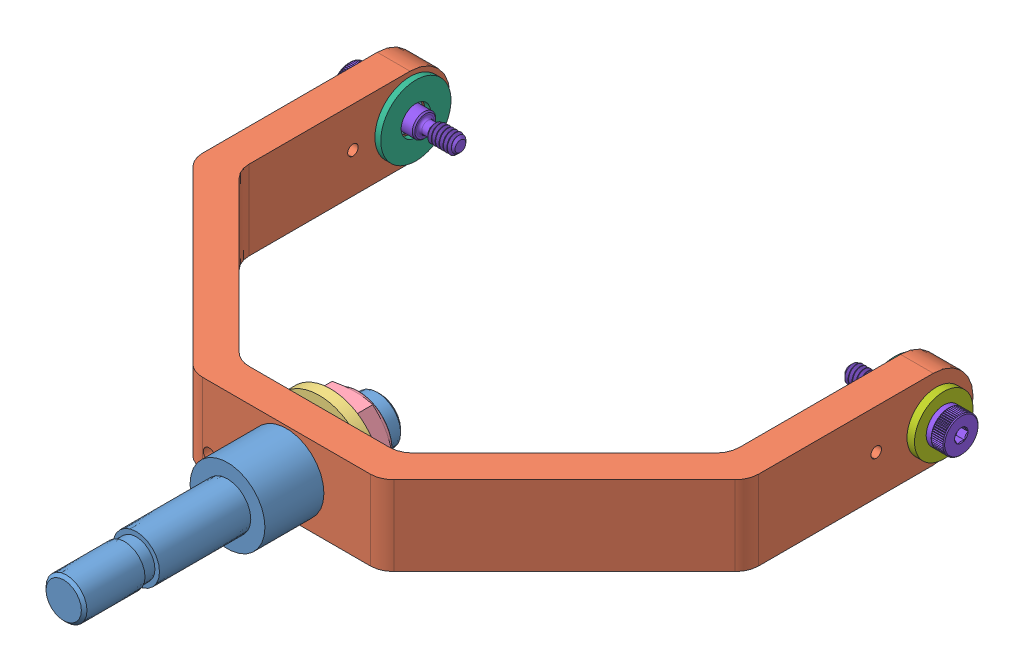
SolidWorks assembly Yoke Prepared, configuration Default. Lengths in mm.
Overall size (166.46 28.57 171.32).
13 component instances, 8 part files, 16 mates.
Components (placement in the parent):
- Yoke Assembly (YK)-1: Yoke Assembly (YK) [Default] at (49.8231 -13.5105 25.623) size (150.88 28.57 171.32)
  - Yoke Rod (YK-2)-1: Yoke Rod (YK-2) [Default] at (-44.1455 25.2929 -11.4146) size (20.32 20.32 85.85)
  - Yoke Fork (YK-1)-1: Yoke Fork (YK-1) [Default] at (-44.1455 14.4979 -65.135) x (1 0 0) z (0 1 0) size (150.88 110.87 21.59)
  - SAE 0.5 Washer (MMC 91083A033)-1: SAE 0.5 Washer (MMC 91083A033) [91083A033] at (-44.1455 25.2929 -23.378) x (0 0 1) z (-1 0 0) size (3.07 26.97 26.97)
  - Nylok Jam Nut 0.5 (MMC 94945A225)-1: Nylok Jam Nut 0.5 (MMC 94945A225) [94945A225] at (-44.1455 25.2929 -23.378) x (0.866025 0.5 0) z (-0.5 0.866025 0) size (19.05 8.3 22)
- Pitch Flange (igus TFI-0405-06)-1: Pitch Flange (igus TFI-0405-06) [Default] at (81.9284 11.7824 -85.867) x (0 0 1) z (-1 0 0) size (12.7 12.7 9.53)
- Pitch Flange (igus TFI-0405-06)-2: Pitch Flange (igus TFI-0405-06) [Default] at (-70.5732 11.7824 -85.867) x (0 -0.924225 -0.381849) z (1 0 0) size (12.7 12.7 9.53)
- Pitch Thrust (MSC 6455356)-1: Pitch Thrust (MSC 6455356) [Default] at (-59.2829 11.7824 -85.867) x (0 0.026708 0.999643) z (-1 0 0) size (19.05 19.05 1.59)
- Pitch Thrust (MSC 6455356)-2: Pitch Thrust (MSC 6455356) [Default] at (72.2256 11.7824 -85.867) x (0 0.026708 0.999643) z (-1 0 0) size (19.05 19.05 1.59)
- SAE 0.25 Washer (MMC 91083A029)-1: SAE 0.25 Washer (MMC 91083A029) [91083A029] at (81.9284 11.7824 -85.867) size (2.03 15.88 15.88)
- SAE 0.25 Washer (MMC 91083A029)-2: SAE 0.25 Washer (MMC 91083A029) [91083A029] at (-72.6052 11.7824 -85.867) size (2.03 15.88 15.88)
- Pitch Shoulder Bolt (MMC 91259A539)-1: Pitch Shoulder Bolt (MMC 91259A539) [91259A539] at (83.9604 11.7824 -85.867) x (0 -1 0) z (0 0 1) size (9.53 30.52 9.53)
- Pitch Shoulder Bolt (MMC 91259A539)-2: Pitch Shoulder Bolt (MMC 91259A539) [91259A539] at (-72.6052 11.7824 -85.867) x (0 -0.381849 0.924225) z (0 -0.924225 -0.381849) size (9.53 30.52 9.53)
Mates (geometry in assembly coordinates):
- Concentric1: concentric aligned: cylinder of Yoke Assembly (YK)-1/Yoke Fork (YK-1)-1 through (-69.7604 11.7824 -85.867) axis (1 0 0) radius 3.9688; cylinder of Pitch Flange (igus TFI-0405-06)-1 through (76.7595 11.7824 -85.867) axis (1 0 0) radius 3.9688
- Coincident1: coincident anti-aligned: plane of Yoke Assembly (YK)-1/Yoke Fork (YK-1)-1 through (81.1156 22.5774 -96.662) normal (1 0 0); plane of Pitch Flange (igus TFI-0405-06)-1 through (81.1156 11.7824 -80.4576) normal (-1 0 0)
- Concentric2: concentric anti-aligned: cylinder of Yoke Assembly (YK)-1/Yoke Fork (YK-1)-1 through (-69.7604 11.7824 -85.867) axis (1 0 0) radius 3.9688; cylinder of Pitch Flange (igus TFI-0405-06)-2 through (-65.4043 11.7824 -85.867) axis (-1 0 0) radius 3.9688
- Coincident2: coincident anti-aligned: plane of Yoke Assembly (YK)-1/Yoke Fork (YK-1)-1 through (-69.7604 22.5774 -39.512) normal (-1 0 0); plane of Pitch Flange (igus TFI-0405-06)-2 through (-69.7604 6.7829 -87.9325) normal (1 0 0)
- Concentric3: concentric anti-aligned: cylinder of Pitch Flange (igus TFI-0405-06)-2 through (-65.8107 11.7824 -85.867) axis (-1 0 0) radius 3.175; cylinder of Pitch Thrust (MSC 6455356)-1 through (-60.8704 11.7824 -85.867) axis (1 0 0) radius 4.0005
- Coincident3: coincident anti-aligned: plane of Yoke Assembly (YK)-1/Yoke Fork (YK-1)-1 through (-60.8704 22.5774 -39.512) normal (1 0 0); plane of Pitch Thrust (MSC 6455356)-1 through (-60.8704 11.7824 -85.867) normal (-1 0 0)
- Concentric4: concentric aligned: cylinder of Pitch Flange (igus TFI-0405-06)-1 through (77.1659 11.7824 -85.867) axis (1 0 0) radius 3.175; cylinder of Pitch Thrust (MSC 6455356)-2 through (70.6381 11.7824 -85.867) axis (1 0 0) radius 4.0005
- Coincident4: coincident anti-aligned: plane of Yoke Assembly (YK)-1/Yoke Fork (YK-1)-1 through (72.2256 22.5774 -39.512) normal (-1 0 0); plane of Pitch Thrust (MSC 6455356)-2 through (72.2256 11.7824 -85.867) normal (1 0 0)
- Concentric5: concentric anti-aligned: cylinder of Pitch Flange (igus TFI-0405-06)-1 through (77.1659 11.7824 -85.867) axis (1 0 0) radius 3.175; cylinder of SAE 0.25 Washer (MMC 91083A029)-1 through (83.9604 11.7824 -85.867) axis (-1 0 0) radius 3.5687
- Coincident5: coincident anti-aligned: plane of Pitch Flange (igus TFI-0405-06)-1 through (81.9284 11.7824 -81.1045) normal (1 0 0); plane of SAE 0.25 Washer (MMC 91083A029)-1 through (81.9284 11.7824 -85.867) normal (-1 0 0)
- Concentric6: concentric aligned: cylinder of Pitch Flange (igus TFI-0405-06)-2 through (-65.8107 11.7824 -85.867) axis (-1 0 0) radius 3.175; cylinder of SAE 0.25 Washer (MMC 91083A029)-2 through (-70.5732 11.7824 -85.867) axis (-1 0 0) radius 3.5687
- Coincident6: coincident anti-aligned: plane of Pitch Flange (igus TFI-0405-06)-2 through (-70.5732 7.3808 -87.6855) normal (-1 0 0); plane of SAE 0.25 Washer (MMC 91083A029)-2 through (-70.5732 11.7824 -85.867) normal (1 0 0)
- Concentric7: concentric aligned: cylinder of SAE 0.25 Washer (MMC 91083A029)-1 through (83.9604 11.7824 -85.867) axis (-1 0 0) radius 3.5687; cylinder of Pitch Shoulder Bolt (MMC 91259A539)-1 through (83.9604 11.7824 -85.867) axis (-1 0 0) radius 3.175
- Coincident7: coincident anti-aligned: plane of SAE 0.25 Washer (MMC 91083A029)-1 through (83.9604 11.7824 -85.867) normal (1 0 0); plane of Pitch Shoulder Bolt (MMC 91259A539)-1 through (83.9604 11.7824 -85.867) normal (-1 0 0)
- Concentric8: concentric anti-aligned: cylinder of SAE 0.25 Washer (MMC 91083A029)-2 through (-70.5732 11.7824 -85.867) axis (-1 0 0) radius 3.5687; cylinder of Pitch Shoulder Bolt (MMC 91259A539)-2 through (-72.6052 11.7824 -85.867) axis (1 0 0) radius 3.175
- Coincident8: coincident anti-aligned: plane of SAE 0.25 Washer (MMC 91083A029)-2 through (-72.6052 11.7824 -85.867) normal (-1 0 0); plane of Pitch Shoulder Bolt (MMC 91259A539)-2 through (-72.6052 11.7824 -85.867) normal (1 0 0)
